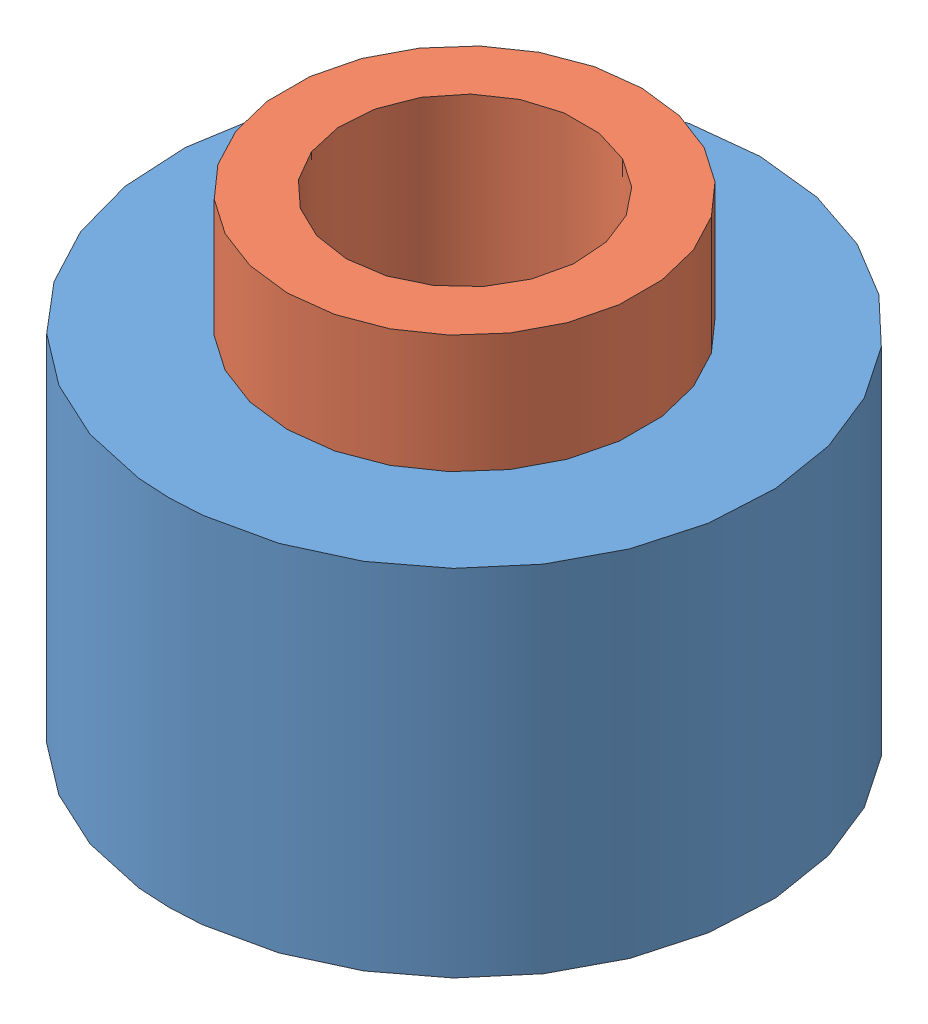
SolidWorks assembly rouleau_complet_D25_H20, configuration Default. Lengths in mm.
Overall size (25 20 25).
2 component instances, 2 part files, 2 mates.
Components (placement in the parent):
- Rouleau_D25_H15-1: Rouleau_D25_H15 [Default] at (-6.5011 -2.8091 0.2436) size (25 15 25)
- Support_Rouleau_D15_H20-1: Support_Rouleau_D15_H20 [Default] at (-6.5011 12.1909 0.2436) size (15 20 15)
Mates (geometry in assembly coordinates):
- Coaxiale1: concentric: cylinder of Rouleau_D25_H15-1 through (-6.5011 12.1909 0.2436) axis (0 -1 0) radius 6.5; cylinder of Support_Rouleau_D15_H20-1 through (-6.5011 19.88 0.2436) axis (0 1 0) radius 6
- Coïncidente1: coincident anti-aligned: plane of Rouleau_D25_H15-1 through (-6.5011 12.1909 0.2436) normal (0 1 0); plane of Support_Rouleau_D15_H20-1 through (-6.5011 12.1909 0.2436) normal (0 -1 0)
